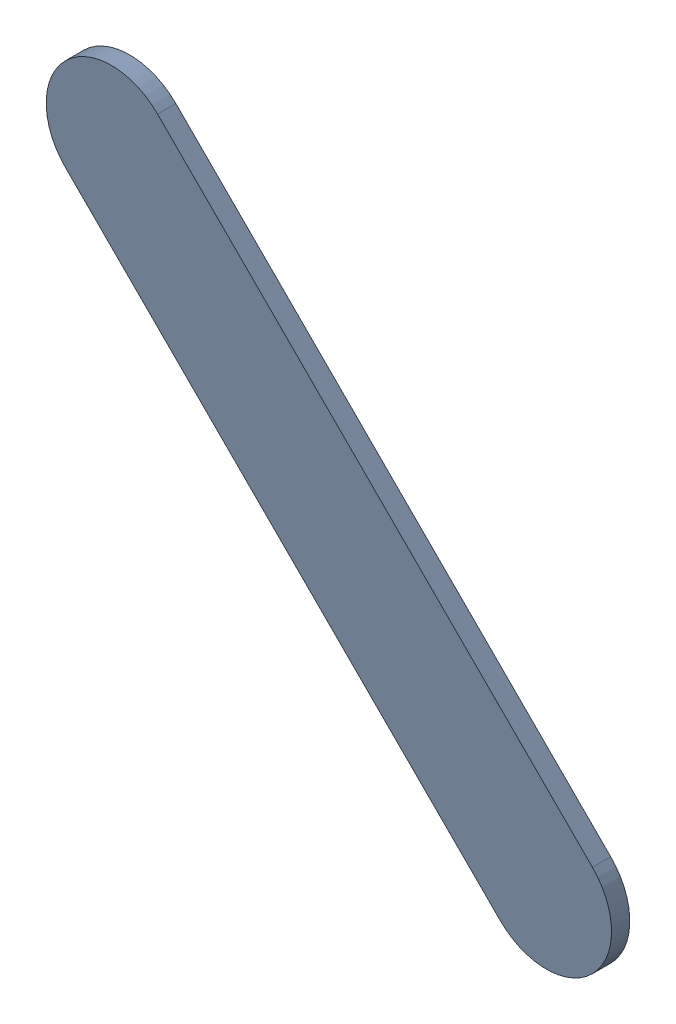
SolidWorks assembly Track (18.353mm,49.947mm)(19.2mm,49.1mm) on Top Layer, configuration Predeterminado. Lengths in mm.
Overall size (1.1 1.1 0.04).
2 component instances, 1 part files, 0 mates.
Components (placement in the parent):
- Track (18.353mm,49.947mm)(19.2mm,49.1mm) on Top Layer-1-1: Track (18.353mm,49.947mm)(19.2mm,49.1mm) on Top Layer-1 [Predeterminado] at (-68.317 -44.187 -0.0457) size (1.1 1.1 0.04)
  - Track (18.353mm,49.947mm)(19.2mm,49.1mm) on Top Layer-Part-1-1: Track (18.353mm,49.947mm)(19.2mm,49.1mm) on Top Layer-Part-1 [Predeterminado] at origin size (1.1 1.1 0.04)
